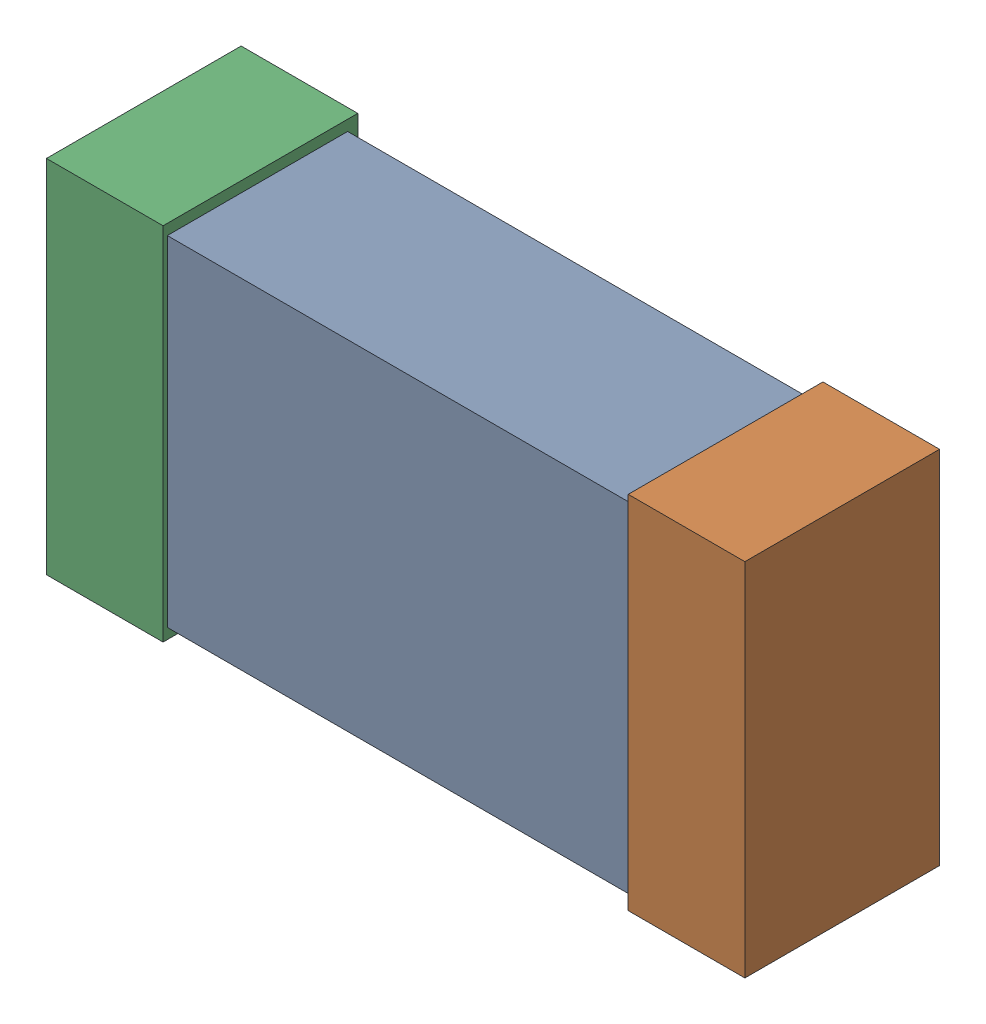
SolidWorks assembly R14, configuration Default. Lengths in mm.
Overall size (1.65 0.85 0.46).
6 component instances, 2 part files, 0 mates.
Components (placement in the parent):
- 432120720_18-1: 432120720_18 [Default] at (31.0957 13.7029 0.025) size (1.5 0.8 0.42)
  - Extruded (12)-1: Extruded (12) [Default] at origin size (1.5 0.8 0.42)
- 432120464_38-1: 432120464_38 [Default] at (31.7815 13.7029 0.001) size (0.28 0.85 0.46)
  - Extruded (11)-1: Extruded (11) [Default] at origin size (0.28 0.85 0.46)
- 432120464_39-1: 432120464_39 [Default] at (30.4099 13.7029 0.001) size (0.28 0.85 0.46)
  - Extruded (11)-1: Extruded (11) [Default] at origin size (0.28 0.85 0.46)
